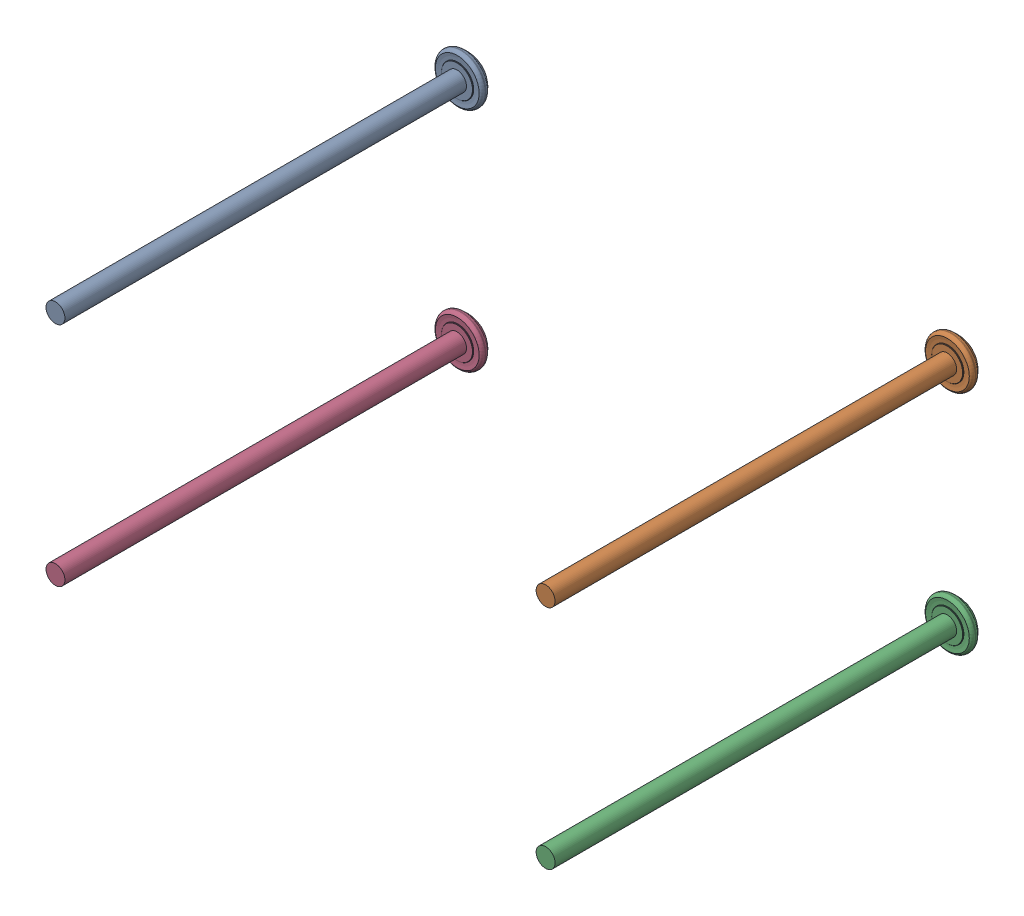
SolidWorks assembly Feetech SCS0009, configuration Default. Lengths in mm.
Overall size (22.81 11.66 17.77).
4 component instances, 1 part files, 0 mates.
Components (placement in the parent):
- 91772A071_NO THREADS_Passivated 18-8 Stainless Steel Pan Head Phillips Screw-1: 91772A071_NO THREADS_Passivated 18-8 Stainless Steel Pan Head Phillips Screw [Default] at (-4.8 4.9736 9.9662) x (1 0 0) z (0 0 -1) size (2.06 2.06 17.77)
- 91772A071_NO THREADS_Passivated 18-8 Stainless Steel Pan Head Phillips Screw-2: 91772A071_NO THREADS_Passivated 18-8 Stainless Steel Pan Head Phillips Screw [Default] at (15.95 4.9736 9.9662) x (1 0 0) z (0 0 -1) size (2.06 2.06 17.77)
- 91772A071_NO THREADS_Passivated 18-8 Stainless Steel Pan Head Phillips Screw-3: 91772A071_NO THREADS_Passivated 18-8 Stainless Steel Pan Head Phillips Screw [Default] at (15.95 -4.6264 9.9662) x (1 0 0) z (0 0 -1) size (2.06 2.06 17.77)
- 91772A071_NO THREADS_Passivated 18-8 Stainless Steel Pan Head Phillips Screw-4: 91772A071_NO THREADS_Passivated 18-8 Stainless Steel Pan Head Phillips Screw [Default] at (-4.8 -4.6264 9.9662) x (1 0 0) z (0 0 -1) size (2.06 2.06 17.77)
